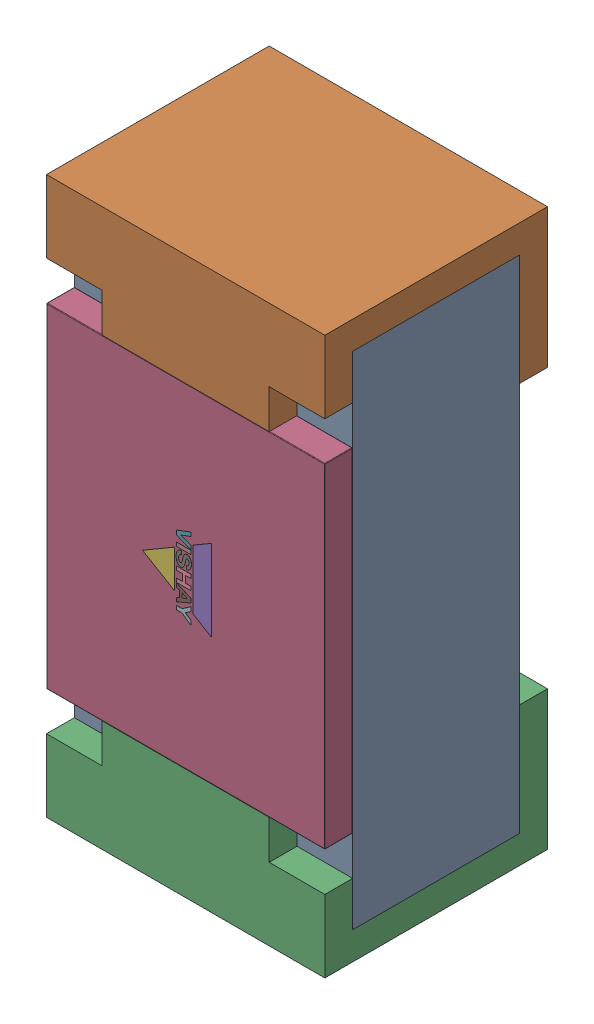
SolidWorks assembly R5.step, configuration Default. Lengths in mm.
Overall size (0.5 1 0.4).
6 component instances, 4 part files, 0 mates.
Components (placement in the parent):
- Res_Vishay_CRCW04021K00FKED_eec.step-1: Res_Vishay_CRCW04021K00FKED_eec.step [Default] at (62.611 62.2089 0) x (0 -1 0) z (0 0 1) size (1 0.5 0.4)
  - body.step-1: body.step [Default] at (0 0 0.35) x (1 0 0) z (0 0 -1) size (0.9 0.5 0.3)
  - pad.step-1: pad.step [Default] at (-0.3133 -0.25 0.4) x (1 0 0) z (0 1 0) size (0.25 0.4 0.5)
  - pad.step-2: pad.step [Default] at (0.3133 0.25 0.4) x (-1 0 0) z (0 -1 0) size (0.25 0.4 0.5)
  - top.step-1: top.step [Default] at (0 0 0.4) x (1 0 0) z (0 0 -1) size (0.6 0.5 0.05)
  - Vishay.step-1: Vishay.step [Default] at (0.0437 -0.9162 0.4) size (0.15 0.12 0)
